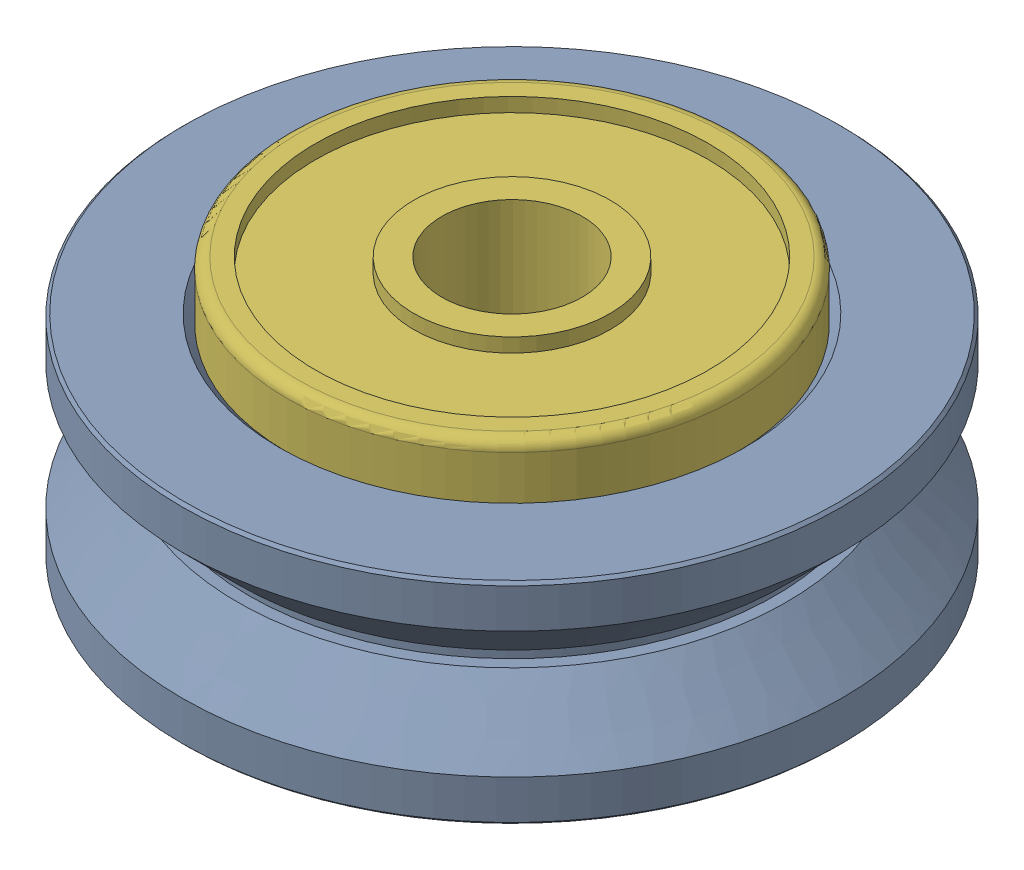
SolidWorks assembly 25203-02, configuration Default. Lengths in mm.
Overall size (23.5 11 23.5).
4 component instances, 3 part files, 0 mates.
Components (placement in the parent):
- 25202-01-1: 25202-01 [Default] at origin size (23.5 7.5 23.5)
- 25196-01-1: 25196-01 [Default] at (0 -3 0) x (0.224141 0 -0.974557) z (-0.974557 0 -0.224141) size (16 5 16)
- 25201-01-1: 25201-01 [Default] at (0 -0.5 0) x (0.992075 0 -0.125646) z (0.125646 0 0.992075) size (10 1 10)
- 25196-01-2: 25196-01 [Default] at (0 3 0) x (-0.996407 0 -0.084695) z (-0.084695 0 0.996407) size (16 5 16)
